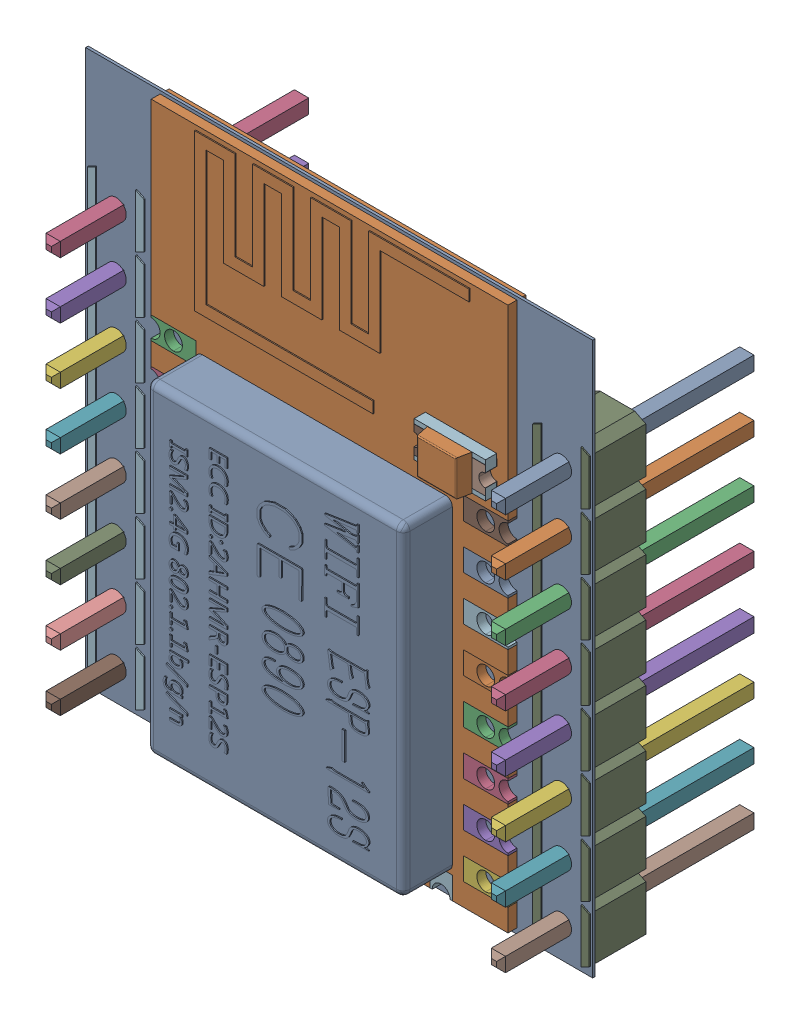
SolidWorks assembly PCB-1, configuration ﾃﾞﾌｫﾙﾄ. Lengths in mm.
Overall size (22.73 24.76 11.54).
50 component instances, 25 part files, 0 mates.
Components (placement in the parent):
- Board-1-1: Board-1 [ﾃﾞﾌｫﾙﾄ] at origin size (22.73 24.76 0.12)
  - Open CASCADE STEP translator 6.8 1.1.1-1: Open CASCADE STEP translator 6.8 1.1.1 [ﾃﾞﾌｫﾙﾄ] at (0 0 -0.1168) size (22.73 24.76 0.12)
- P3-1: P3 [ﾃﾞﾌｫﾙﾄ] at origin size (16 24.38 3.05)
  - 0411-2-1: 0411-2 [ﾃﾞﾌｫﾙﾄ] at (11.34 12.4403 0) x (0 1 0) z (-1 0 0) size (24.38 3.05 16)
    - User_Library-ESP8266-12E_PCB1-1: User_Library-ESP8266-12E_PCB1 [ﾃﾞﾌｫﾙﾄ] x (-1 0 0) z (0 0 1) size (24.38 0.8 16)
    - User_Library-ESP8266-12E_Pin1-1: User_Library-ESP8266-12E_Pin1 [ﾃﾞﾌｫﾙﾄ] at (3.31 0 8) x (-1 0 0) z (0 -1 0) size (1 2 0.8)
    - User_Library-ESP8266-12E_Pin1-2: User_Library-ESP8266-12E_Pin1 [ﾃﾞﾌｫﾙﾄ] at (1.31 0 8) x (-1 0 0) z (0 -1 0) size (1 2 0.8)
    - User_Library-ESP8266-12E_Pin1-3: User_Library-ESP8266-12E_Pin1 [ﾃﾞﾌｫﾙﾄ] at (-0.69 0 8) x (-1 0 0) z (0 -1 0) size (1 2 0.8)
    - User_Library-ESP8266-12E_Pin1-4: User_Library-ESP8266-12E_Pin1 [ﾃﾞﾌｫﾙﾄ] at (-2.69 0 8) x (-1 0 0) z (0 -1 0) size (1 2 0.8)
    - User_Library-ESP8266-12E_Pin1-5: User_Library-ESP8266-12E_Pin1 [ﾃﾞﾌｫﾙﾄ] at (-4.69 0 8) x (-1 0 0) z (0 -1 0) size (1 2 0.8)
    - User_Library-ESP8266-12E_Pin1-6: User_Library-ESP8266-12E_Pin1 [ﾃﾞﾌｫﾙﾄ] at (-6.69 0 8) x (-1 0 0) z (0 -1 0) size (1 2 0.8)
    - User_Library-ESP8266-12E_Pin1-7: User_Library-ESP8266-12E_Pin1 [ﾃﾞﾌｫﾙﾄ] at (-8.69 0 8) x (-1 0 0) z (0 -1 0) size (1 2 0.8)
    - User_Library-ESP8266-12E_Pin1-8: User_Library-ESP8266-12E_Pin1 [ﾃﾞﾌｫﾙﾄ] at (-10.69 0 8) x (-1 0 0) z (0 -1 0) size (1 2 0.8)
    - User_Library-ESP8266-12E_Pin1-9: User_Library-ESP8266-12E_Pin1 [ﾃﾞﾌｫﾙﾄ] at (3.31 0 -8) x (1 0 0) z (0 -1 0) size (1 2 0.8)
    - User_Library-ESP8266-12E_Pin1-10: User_Library-ESP8266-12E_Pin1 [ﾃﾞﾌｫﾙﾄ] at (-0.69 0 -8) x (1 0 0) z (0 -1 0) size (1 2 0.8)
    - User_Library-ESP8266-12E_Pin1-11: User_Library-ESP8266-12E_Pin1 [ﾃﾞﾌｫﾙﾄ] at (1.31 0 -8) x (1 0 0) z (0 -1 0) size (1 2 0.8)
    - User_Library-ESP8266-12E_Pin1-12: User_Library-ESP8266-12E_Pin1 [ﾃﾞﾌｫﾙﾄ] at (-2.69 0 -8) x (1 0 0) z (0 -1 0) size (1 2 0.8)
    - User_Library-ESP8266-12E_Pin1-13: User_Library-ESP8266-12E_Pin1 [ﾃﾞﾌｫﾙﾄ] at (-4.69 0 -8) x (1 0 0) z (0 -1 0) size (1 2 0.8)
    - User_Library-ESP8266-12E_Pin1-14: User_Library-ESP8266-12E_Pin1 [ﾃﾞﾌｫﾙﾄ] at (-6.69 0 -8) x (1 0 0) z (0 -1 0) size (1 2 0.8)
    - User_Library-ESP8266-12E_Pin1-15: User_Library-ESP8266-12E_Pin1 [ﾃﾞﾌｫﾙﾄ] at (-8.69 0 -8) x (1 0 0) z (0 -1 0) size (1 2 0.8)
    - User_Library-ESP8266-12E_Pin1-16: User_Library-ESP8266-12E_Pin1 [ﾃﾞﾌｫﾙﾄ] at (-10.69 0 -8) x (1 0 0) z (0 -1 0) size (1 2 0.8)
    - User_Library-ESP8266-12E_Pin2-1: User_Library-ESP8266-12E_Pin2 [ﾃﾞﾌｫﾙﾄ] at (-12.19 0 5) x (0 0 1) z (0 1 0) size (1 1 0.8)
    - User_Library-ESP8266-12E_Pin2-2: User_Library-ESP8266-12E_Pin2 [ﾃﾞﾌｫﾙﾄ] at (-12.19 0 3) x (0 0 -1) z (0 -1 0) size (1 1 0.8)
    - User_Library-ESP8266-12E_Pin2-3: User_Library-ESP8266-12E_Pin2 [ﾃﾞﾌｫﾙﾄ] at (-12.19 0 1) x (0 0 1) z (0 1 0) size (1 1 0.8)
    - User_Library-ESP8266-12E_Pin2-4: User_Library-ESP8266-12E_Pin2 [ﾃﾞﾌｫﾙﾄ] at (-12.19 0 -1) x (0 0 1) z (0 1 0) size (1 1 0.8)
    - User_Library-ESP8266-12E_Pin2-5: User_Library-ESP8266-12E_Pin2 [ﾃﾞﾌｫﾙﾄ] at (-12.19 0 -3) x (0 0 1) z (0 1 0) size (1 1 0.8)
    - User_Library-ESP8266-12E_Pin2-6: User_Library-ESP8266-12E_Pin2 [ﾃﾞﾌｫﾙﾄ] at (-12.19 0 -5) x (0 0 1) z (0 1 0) size (1 1 0.8)
    - User_Library-ESP8266-12E_Lid-1: User_Library-ESP8266-12E_Lid [ﾃﾞﾌｫﾙﾄ] at (-3.84 -1.5 0.25) x (0 0 -1) z (0 -1 0) size (11.5 14.5 2.25)
    - User_Library-ESP8266-12E_Antenne-1: User_Library-ESP8266-12E_Antenne [ﾃﾞﾌｫﾙﾄ] at (4.99 -0.425 6) x (0 0 -1) z (0 -1 0) size (12.3 7 0.05)
    - User_Library-ESP8266-12E_Surface_Mount_Chip_LED_3.2x1.6mm-1: User_Library-ESP8266-12E_Surface_Mount_Chip_LED_3.2x1.6mm [ﾃﾞﾌｫﾙﾄ] at (6.19 -0.41 -7.5) x (0 0 1) z (0 -1 0) size (3.2 1.6 1.13)
- Open CASCADE STEP translator 6.8 1.3-1: Open CASCADE STEP translator 6.8 1.3 [ﾃﾞﾌｫﾙﾄ] at origin size (2.54 20.32 11.54)
  - Header8_2.54mm-1: Header8_2.54mm [ﾃﾞﾌｫﾙﾄ] at (1.3969 10.3123 -1.2168) x (0 -1 0) z (1 0 0) size (0.64 11.54 0.64)
  - Header8_2.54mm-2-1: Header8_2.54mm-2 [ﾃﾞﾌｫﾙﾄ] at (1.3969 10.3123 -1.2168) x (0 -1 0) z (1 0 0) size (0.64 11.54 0.64)
  - Header8_2.54mm-3-1: Header8_2.54mm-3 [ﾃﾞﾌｫﾙﾄ] at (1.3969 10.3123 -1.2168) x (0 -1 0) z (1 0 0) size (0.64 11.54 0.64)
  - Header8_2.54mm-4-1: Header8_2.54mm-4 [ﾃﾞﾌｫﾙﾄ] at (1.3969 10.3123 -1.2168) x (0 -1 0) z (1 0 0) size (0.64 11.54 0.64)
  - Header8_2.54mm-5-1: Header8_2.54mm-5 [ﾃﾞﾌｫﾙﾄ] at (1.3969 10.3123 -1.2168) x (0 -1 0) z (1 0 0) size (0.64 11.54 0.64)
  - Header8_2.54mm-6-1: Header8_2.54mm-6 [ﾃﾞﾌｫﾙﾄ] at (1.3969 10.3123 -1.2168) x (0 -1 0) z (1 0 0) size (0.64 11.54 0.64)
  - Header8_2.54mm-7-1: Header8_2.54mm-7 [ﾃﾞﾌｫﾙﾄ] at (1.3969 10.3123 -1.2168) x (0 -1 0) z (1 0 0) size (0.64 11.54 0.64)
  - Header8_2.54mm-8-1: Header8_2.54mm-8 [ﾃﾞﾌｫﾙﾄ] at (1.3969 10.3123 -1.2168) x (0 -1 0) z (1 0 0) size (0.64 11.54 0.64)
  - Header8_2.54mm-9-1: Header8_2.54mm-9 [ﾃﾞﾌｫﾙﾄ] at (1.3969 10.3123 -1.2168) x (0 -1 0) z (1 0 0) size (20.32 2.54 2.54)
- 1-10-1: 1-10 [ﾃﾞﾌｫﾙﾄ] at origin size (2.54 20.32 11.54)
  - Header8_2.54mm_RGB255-1: Header8_2.54mm_RGB255 [ﾃﾞﾌｫﾙﾄ] at (21.3613 10.3123 -1.2168) x (0 -1 0) z (1 0 0) size (0.64 11.54 0.64)
  - Header8_2.54mm_RGB255-11-1: Header8_2.54mm_RGB255-11 [ﾃﾞﾌｫﾙﾄ] at (21.3613 10.3123 -1.2168) x (0 -1 0) z (1 0 0) size (0.64 11.54 0.64)
  - Header8_2.54mm_RGB255-12-1: Header8_2.54mm_RGB255-12 [ﾃﾞﾌｫﾙﾄ] at (21.3613 10.3123 -1.2168) x (0 -1 0) z (1 0 0) size (0.64 11.54 0.64)
  - Header8_2.54mm_RGB255-13-1: Header8_2.54mm_RGB255-13 [ﾃﾞﾌｫﾙﾄ] at (21.3613 10.3123 -1.2168) x (0 -1 0) z (1 0 0) size (0.64 11.54 0.64)
  - Header8_2.54mm_RGB255-14-1: Header8_2.54mm_RGB255-14 [ﾃﾞﾌｫﾙﾄ] at (21.3613 10.3123 -1.2168) x (0 -1 0) z (1 0 0) size (0.64 11.54 0.64)
  - Header8_2.54mm_RGB255-15-1: Header8_2.54mm_RGB255-15 [ﾃﾞﾌｫﾙﾄ] at (21.3613 10.3123 -1.2168) x (0 -1 0) z (1 0 0) size (0.64 11.54 0.64)
  - Header8_2.54mm_RGB255-16-1: Header8_2.54mm_RGB255-16 [ﾃﾞﾌｫﾙﾄ] at (21.3613 10.3123 -1.2168) x (0 -1 0) z (1 0 0) size (0.64 11.54 0.64)
  - Header8_2.54mm_RGB255-17-1: Header8_2.54mm_RGB255-17 [ﾃﾞﾌｫﾙﾄ] at (21.3613 10.3123 -1.2168) x (0 -1 0) z (1 0 0) size (0.64 11.54 0.64)
  - Header8_2.54mm_RGB255-18-1: Header8_2.54mm_RGB255-18 [ﾃﾞﾌｫﾙﾄ] at (21.3613 10.3123 -1.2168) x (0 -1 0) z (1 0 0) size (20.32 2.54 2.54)
